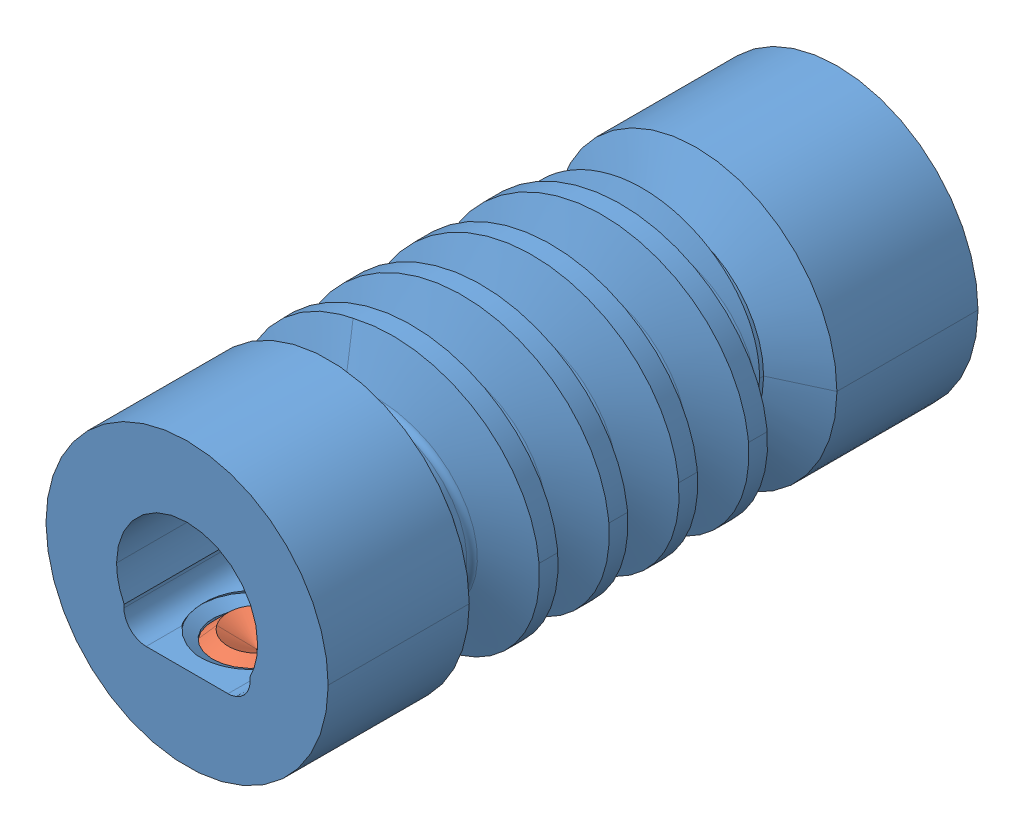
SolidWorks assembly wormgear, configuration Default. Lengths in mm.
Overall size (12.7 13.35 29.62).
4 component instances, 2 part files, 0 mates.
Components (placement in the parent):
- 615462 assembly.STEP-1: 615462 assembly.STEP [Default] at origin size (12.7 13.35 29.62)
  - 615462.STEP-1: 615462.STEP [Default] at (-12.1392 4.7088 3.3043) size (12.7 13.35 29.25)
  - 632134_91375A436.STEP-1: 632134_91375A436.STEP [Default] at (-12.1392 0.1384 14.7533) x (0.578664 0 0.815566) z (0 -1 0) size (4.83 4.83 3.18)
  - 632134_91375A436.STEP-2: 632134_91375A436.STEP [Default] at (-12.1392 0.1384 -8.1448) x (-0.562691 0 -0.826667) z (0 -1 0) size (4.83 4.83 3.18)
